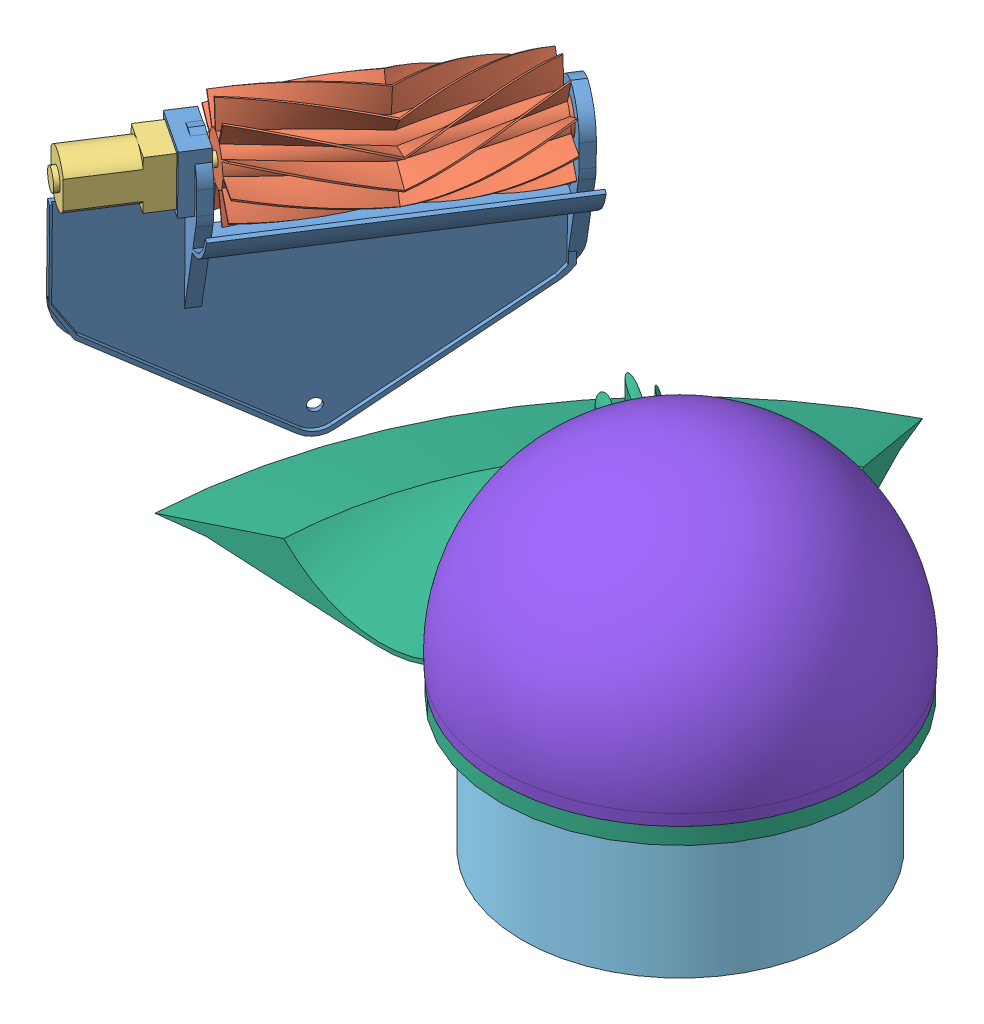
SolidWorks assembly Broomer, configuration Default. Lengths in mm.
Overall size (330.45 165.04 262.46).
13 component instances, 10 part files, 5 mates.
Components (placement in the parent):
- Drone_22-1: Drone_22 [Default] at (-250.4429 -140.8547 -81.3529) x (-0.543945 0 0.839121) z (0.826908 0.169988 0.536029) size (93.99 80.43 40.32)
  - Drone frame22-1: Drone frame22 [Default] at (0 -134.9098 20.0039) x (1 0 0) z (0 -0.979471 0.201586) size (93.99 26.74 70.08)
  - drone brush 12-1: drone brush 12 [Default] at (0 -127.0598 20.9407) x (1 0 0) z (0 0.9287 0.370831) size (62.02 24.54 24.51)
  - micro dc motor-2: micro dc motor [Default] at (22.85 -127.0598 20.9407) x (0 0.979471 -0.201586) z (0 0.201586 0.979471) size (12 33.91 9.85)
  - Part7563-1: Part7563 [Default] at (0 -134.7082 20.9834) x (1 0 0) z (0 0.201586 0.979471)
- Socle-1: Socle [Default] at (-85.6088 -0.4615 -37.804) x (-0.368031 0 -0.929814) z (0.929814 0 -0.368031) size (223 85.89 212.78)
  - ruban spool-1: ruban spool [Default] at (-68.2283 53.2463 21.9215) x (0.580037 0 0.81459) z (-0.814589 -0.001264 0.580037) size (11 30 30)
  - servo holder Base-1: servo holder Base [Default] at (-70.0506 22.8363 23.2374) x (-0.546944 0 -0.837169) z (0.837169 0 -0.546944) size (76.56 30.68 76.56)
  - socle base-1: socle base [Default] at (-53.6131 0 21.3376) x (0.837169 0 -0.546944) z (0.546944 0 0.837169) size (65.04 22 76) (hidden)
  - servo holderb-1: servo holderb [Default] at (-65.4545 53.1463 17.1106) x (0.81459 0 -0.580037) z (0 1 0) size (178.02 134.45 74.68)
  - FS90R-1: FS90R [Default] at (-58.7617 3.3063 29.1807) x (-0.546944 0 -0.837169) z (0.837169 0 -0.546944) size (31.91 30.84 12.2)
  - FS90R-2: FS90R [Default] at (-89.9256 47.1463 1.967) x (0.81459 0 -0.580037) z (0 -1 0) size (31.91 30.84 12.2)
  - dronecover-1: dronecover [Default] at (-65.4545 36.1463 17.1106) x (0.81459 0 -0.580037) z (0 1 0) size (87.94 88.06 49.74)
Mates (geometry in assembly coordinates):
- Parallel6: parallel aligned: plane of Drone_22-1/Drone frame22-1 through (-253.3857 -44.5194 -83.2605) normal (-0.543945 0 0.839121); plane of Socle-1/servo holderb-1 through (-72.6309 59.6849 -8.3956) normal (-0.543945 0 0.839121)
- Coincident28: coincident: circle of Socle-1/servo holder Base-1
- Coincident29: coincident anti-aligned: plane of Socle-1/servo holder Base-1 through (-35.3889 0 14.5961) normal (0 -1 0)
- Tangent10: tangent: face of Drone_22-1/drone brush 12-1; plane of assembly through (0 0 0) normal (0 1 0)
- Coincident30: coincident: point of Drone_22-1/drone brush 12-1; plane of Socle-1/servo holderb-1 through (-72.6309 59.6849 -8.3956) normal (-0.543945 0 0.839121)
